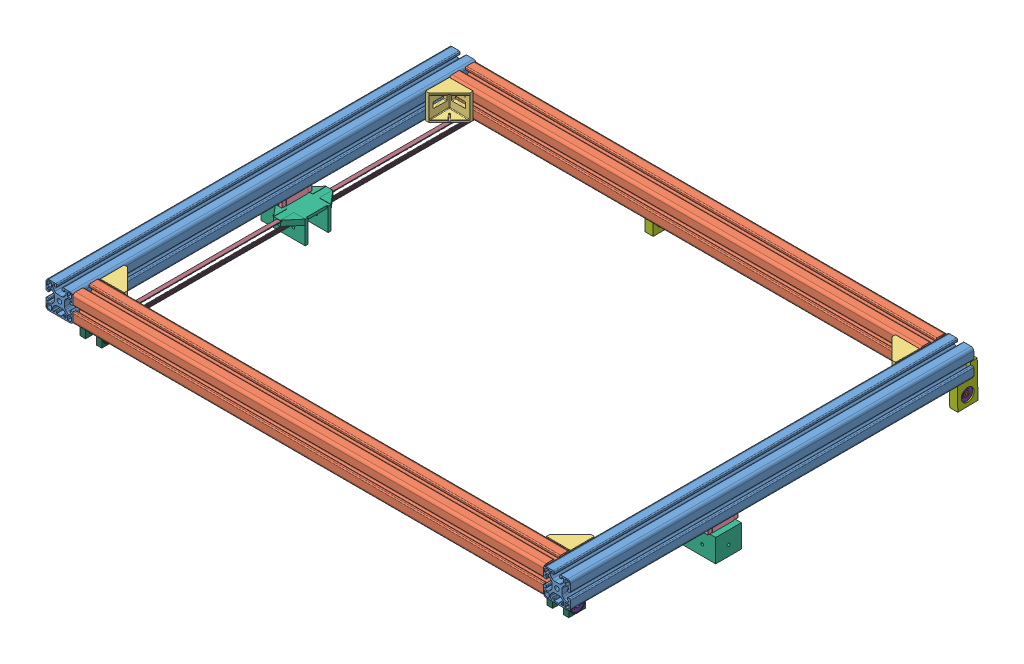
SolidWorks assembly y_axis, configuration Standard. Lengths in mm.
Overall size (783 87 614.14).
164 component instances, 17 part files, 52 mates.
Components (placement in the parent):
- 600mm_Motedis Profile 40x40 3N I-Type slot 8-1: 600mm_Motedis Profile 40x40 3N I-Type slot 8 [Standard] at (-18.8748 -20.0266 -250) size (40 40 600)
- 700mm_Motedis Profile 40x40 3N I-Type slot 8-1: 700mm_Motedis Profile 40x40 3N I-Type slot 8 [Standard] at (-282.8748 -20.0266 186) x (0 0 -1) z (1 0 0) size (40 40 700)
- bracket_40-1: bracket_40 [Standard] at (17.1252 -0.1016 190) x (-1 0 0) z (0 1 0) size (38.54 38.54 38)
- bracket_40-2: bracket_40 [Standard] at (17.1252 -0.1266 710) x (-1 0 0) z (0 -1 0) size (38.54 38.54 38)
- bracket_40-4: bracket_40 [Standard] at (717.1252 -0.1016 710) x (1 0 0) z (0 1 0) size (38.54 38.54 38)
- 700mm_Motedis Profile 40x40 3N I-Type slot 8-2: 700mm_Motedis Profile 40x40 3N I-Type slot 8 [Standard] at (1017.1252 -20.0266 714) x (0 0 1) z (-1 0 0) size (40 40 700)
- 600mm_Motedis Profile 40x40 3N I-Type slot 8-2: 600mm_Motedis Profile 40x40 3N I-Type slot 8 [Standard] at (753.1252 -20.0266 1150) x (-1 0 0) z (0 0 -1) size (40 40 600)
- bracket_40-5: bracket_40 [Standard] at (717.1252 0.0484 190) x (0 0 -1) z (0 1 0) size (38.54 38.54 38)
- MGN12H 1 R 500 ZF H M SS_FILE-1: MGN12H 1 R 500 ZF H M SS_FILE [Standard] at (802.4844 21.1866 187.5) x (1 0 0) z (0 -1 0) size (27 500 13) (flexible)
  - MGN12H 1 R 500 ZF H M SS_FILE-1: MGN12H 1 R 500 ZF H M SS_FILE [Standard] at (-65.3592 306.5221 39.2132) size (27 46.39 10)
  - MGN12H 1 R 500 ZF H M SS_FILE_1-1: MGN12H 1 R 500 ZF H M SS_FILE_1 [Standard] at (-65.3592 0 39.2132) size (12 500 8)
- MGN12H 1 R 500 ZF H M SS_FILE-2: MGN12H 1 R 500 ZF H M SS_FILE [Standard] at (62.4844 19.1866 187.5) x (1 0 0) z (0 -1 0) size (27 500 13) (flexible)
  - MGN12H 1 R 500 ZF H M SS_FILE-1: MGN12H 1 R 500 ZF H M SS_FILE [Standard] at (-65.3592 200.1469 39.2132) size (27 46.39 10)
  - MGN12H 1 R 500 ZF H M SS_FILE_1-1: MGN12H 1 R 500 ZF H M SS_FILE_1 [Standard] at (-65.3592 0 39.2132) size (12 500 8)
- mount_xaxis-1: mount_xaxis [Standard] at (9.6252 -37.0266 409.8469) size (66 34.4 78)
- mount_xaxis-2: mount_xaxis [Standard] at (724.6252 -35.0266 516.2221) x (-1 0 0) z (0 0 -1) size (66 34.4 78)
- drive_shaft_assembled-1: drive_shaft_assembled [Standard] at (97.0434 -122.3621 157.2312) x (0 -0.997563 0.069767) z (1 0 0) size (57.5 34.88 775) (flexible)
  - Lagerbock_assembled-1: Lagerbock_assembled [Standard] at (-81.1418 -2.5498 157.2355) x (0.069767 -0.997563 0) z (0 0 1) size (30 55 12)
    - Lagerbock-1: Lagerbock [Standard] at (0.8863 -1.2135 34) size (30 55 12)
    - 608-2Z-1: 608-2Z [Standard] at (0.8863 -1.2135 44) x (0 0 -1) z (1 0 0) size (7 22 22)
      - 608-2Z_PART1-1: 608-2Z_PART1 [Standard] at origin size (7 19.2 19.2)
      - 608-2Z_PART2-1: 608-2Z_PART2 [Standard] at origin size (7 22 22)
      - 608-2Z_PART3-1: 608-2Z_PART3 [Standard] at origin size (3.97 3.97 3.97)
      - 608-2Z_PART3-2: 608-2Z_PART3 [Standard] x (1 0 0) z (0 0.781831 0.62349) size (3.97 3.97 3.97)
      - 608-2Z_PART3-3: 608-2Z_PART3 [Standard] x (1 0 0) z (0 0.974928 -0.222521) size (3.97 3.97 3.97)
      - 608-2Z_PART3-4: 608-2Z_PART3 [Standard] x (1 0 0) z (0 0.433884 -0.900969) size (3.97 3.97 3.97)
      - 608-2Z_PART3-5: 608-2Z_PART3 [Standard] x (1 0 0) z (0 -0.433884 -0.900969) size (3.97 3.97 3.97)
      - 608-2Z_PART3-6: 608-2Z_PART3 [Standard] x (1 0 0) z (0 -0.974928 -0.222521) size (3.97 3.97 3.97)
      - 608-2Z_PART3-7: 608-2Z_PART3 [Standard] x (1 0 0) z (0 -0.781831 0.62349) size (3.97 3.97 3.97)
      - 608-2Z_PART4-1: 608-2Z_PART4 [Standard] at origin
      - 608-2Z_PART4-2: 608-2Z_PART4 [Standard] x (1 0 0) z (0 0.781831 0.62349)
      - 608-2Z_PART4-3: 608-2Z_PART4 [Standard] x (1 0 0) z (0 0.974928 -0.222521)
      - 608-2Z_PART4-4: 608-2Z_PART4 [Standard] x (1 0 0) z (0 0.433884 -0.900969)
      - 608-2Z_PART4-5: 608-2Z_PART4 [Standard] x (1 0 0) z (0 -0.433884 -0.900969)
      - 608-2Z_PART4-6: 608-2Z_PART4 [Standard] x (1 0 0) z (0 -0.974928 -0.222521)
      - 608-2Z_PART4-7: 608-2Z_PART4 [Standard] x (1 0 0) z (0 -0.781831 0.62349)
  - Lagerbock_assembled-2: Lagerbock_assembled [Standard] at (-81.1627 -2.5255 610.0818) x (0.091028 -0.995848 0) z (0 0 1) size (30 55 12)
    - Lagerbock-1: Lagerbock [Standard] at (0.8863 -1.2135 34) size (30 55 12)
    - 608-2Z-1: 608-2Z [Standard] at (0.8863 -1.2135 44) x (0 0 -1) z (1 0 0) size (7 22 22)
      - 608-2Z_PART1-1: 608-2Z_PART1 [Standard] at origin size (7 19.2 19.2)
      - 608-2Z_PART2-1: 608-2Z_PART2 [Standard] at origin size (7 22 22)
      - 608-2Z_PART3-1: 608-2Z_PART3 [Standard] at origin size (3.97 3.97 3.97)
      - 608-2Z_PART3-2: 608-2Z_PART3 [Standard] x (1 0 0) z (0 0.781831 0.62349) size (3.97 3.97 3.97)
      - 608-2Z_PART3-3: 608-2Z_PART3 [Standard] x (1 0 0) z (0 0.974928 -0.222521) size (3.97 3.97 3.97)
      - 608-2Z_PART3-4: 608-2Z_PART3 [Standard] x (1 0 0) z (0 0.433884 -0.900969) size (3.97 3.97 3.97)
      - 608-2Z_PART3-5: 608-2Z_PART3 [Standard] x (1 0 0) z (0 -0.433884 -0.900969) size (3.97 3.97 3.97)
      - 608-2Z_PART3-6: 608-2Z_PART3 [Standard] x (1 0 0) z (0 -0.974928 -0.222521) size (3.97 3.97 3.97)
      - 608-2Z_PART3-7: 608-2Z_PART3 [Standard] x (1 0 0) z (0 -0.781831 0.62349) size (3.97 3.97 3.97)
      - 608-2Z_PART4-1: 608-2Z_PART4 [Standard] at origin
      - 608-2Z_PART4-2: 608-2Z_PART4 [Standard] x (1 0 0) z (0 0.781831 0.62349)
      - 608-2Z_PART4-3: 608-2Z_PART4 [Standard] x (1 0 0) z (0 0.974928 -0.222521)
      - 608-2Z_PART4-4: 608-2Z_PART4 [Standard] x (1 0 0) z (0 0.433884 -0.900969)
      - 608-2Z_PART4-5: 608-2Z_PART4 [Standard] x (1 0 0) z (0 -0.433884 -0.900969)
      - 608-2Z_PART4-6: 608-2Z_PART4 [Standard] x (1 0 0) z (0 -0.974928 -0.222521)
      - 608-2Z_PART4-7: 608-2Z_PART4 [Standard] x (1 0 0) z (0 -0.781831 0.62349)
  - drive_shaft-1: drive_shaft [Standard] at (-82.2905 -3.5186 -112.9182) x (0 0 -1) z (0.760817 0.648966 0) size (770 8 8)
  - Pulley 1-1: Pulley 1 [Default] at (-82.2905 -3.5186 -83.5075) x (0 0 1) z (-0.994592 0.103863 0) size (14.8 16 16)
  - Pulley 1-2: Pulley 1 [Default] at (-82.2905 -3.5186 151.8444) x (0 0 1) z (-0.382013 0.924157 0) size (14.8 16 16)
  - Pulley 1-3: Pulley 1 [Default] at (-82.2905 -3.5186 610.1722) x (0 0 1) z (-0.74763 0.664116 0) size (14.8 16 16)
  - Lagerbock_assembled-3: Lagerbock_assembled [Standard] at (-81.1418 -2.5498 -152.9182) x (0.069767 -0.997563 0) z (0 0 1) size (30 55 12)
    - Lagerbock-1: Lagerbock [Standard] at (0.8863 -1.2135 34) size (30 55 12)
    - 608-2Z-1: 608-2Z [Standard] at (0.8863 -1.2135 44) x (0 0 -1) z (1 0 0) size (7 22 22)
      - 608-2Z_PART1-1: 608-2Z_PART1 [Standard] at origin size (7 19.2 19.2)
      - 608-2Z_PART2-1: 608-2Z_PART2 [Standard] at origin size (7 22 22)
      - 608-2Z_PART3-1: 608-2Z_PART3 [Standard] at origin size (3.97 3.97 3.97)
      - 608-2Z_PART3-2: 608-2Z_PART3 [Standard] x (1 0 0) z (0 0.781831 0.62349) size (3.97 3.97 3.97)
      - 608-2Z_PART3-3: 608-2Z_PART3 [Standard] x (1 0 0) z (0 0.974928 -0.222521) size (3.97 3.97 3.97)
      - 608-2Z_PART3-4: 608-2Z_PART3 [Standard] x (1 0 0) z (0 0.433884 -0.900969) size (3.97 3.97 3.97)
      - 608-2Z_PART3-5: 608-2Z_PART3 [Standard] x (1 0 0) z (0 -0.433884 -0.900969) size (3.97 3.97 3.97)
      - 608-2Z_PART3-6: 608-2Z_PART3 [Standard] x (1 0 0) z (0 -0.974928 -0.222521) size (3.97 3.97 3.97)
      - 608-2Z_PART3-7: 608-2Z_PART3 [Standard] x (1 0 0) z (0 -0.781831 0.62349) size (3.97 3.97 3.97)
      - 608-2Z_PART4-1: 608-2Z_PART4 [Standard] at origin
      - 608-2Z_PART4-2: 608-2Z_PART4 [Standard] x (1 0 0) z (0 0.781831 0.62349)
      - 608-2Z_PART4-3: 608-2Z_PART4 [Standard] x (1 0 0) z (0 0.974928 -0.222521)
      - 608-2Z_PART4-4: 608-2Z_PART4 [Standard] x (1 0 0) z (0 0.433884 -0.900969)
      - 608-2Z_PART4-5: 608-2Z_PART4 [Standard] x (1 0 0) z (0 -0.433884 -0.900969)
      - 608-2Z_PART4-6: 608-2Z_PART4 [Standard] x (1 0 0) z (0 -0.974928 -0.222521)
      - 608-2Z_PART4-7: 608-2Z_PART4 [Standard] x (1 0 0) z (0 -0.781831 0.62349)
- DYNAMIC-BLK-BELT-0.24W-4: DYNAMIC-BLK-BELT-0.24W [Default] at (717.2057 -46.3441 435) x (0 0 1) z (0 -1 0) size (573.27 6.02 13.27)
  - LINEAR-BLK-BELT-0.24W-1: LINEAR-BLK-BELT-0.24W [16.125"] at origin size (560 6.02 1.34)
  - RADUIS-BLK-BELT-0.24W-1: RADUIS-BLK-BELT-0.24W [Ø1.000] at (280 0 -6.3175) x (-1 0 0) z (0 0 -1) size (6.64 6.02 13.27)
  - RADUIS-BLK-BELT-0.24W-2: RADUIS-BLK-BELT-0.24W [Ø1.000] at (-280 0 -6.3175) size (6.64 6.02 13.27)
  - LINEAR-BLK-BELT-0.24W-2: LINEAR-BLK-BELT-0.24W [16.125"] at (0 0 -12.635) x (1 0 0) z (0 0 -1) size (560 6.02 1.34)
- DYNAMIC-BLK-BELT-0.24W-5: DYNAMIC-BLK-BELT-0.24W [Default] at (22.5458 -46.3441 435) x (0 0 1) z (0 -1 0) size (573.27 6.02 13.27)
  - LINEAR-BLK-BELT-0.24W-1: LINEAR-BLK-BELT-0.24W [16.125"] at origin size (560 6.02 1.34)
  - RADUIS-BLK-BELT-0.24W-1: RADUIS-BLK-BELT-0.24W [Ø1.000] at (280 0 -6.3175) x (-1 0 0) z (0 0 -1) size (6.64 6.02 13.27)
  - RADUIS-BLK-BELT-0.24W-2: RADUIS-BLK-BELT-0.24W [Ø1.000] at (-280 0 -6.3175) size (6.64 6.02 13.27)
  - LINEAR-BLK-BELT-0.24W-2: LINEAR-BLK-BELT-0.24W [16.125"] at (0 0 -12.635) x (1 0 0) z (0 0 -1) size (560 6.02 1.34)
- return_pully-1: return_pully [Standard] at (20.0584 -68.5266 714.9501) x (-1 0 0) z (0 1 0) size (38 45 34)
  - return_pully_holder-1: return_pully_holder [Standard] at (-1.4973 -12.4501 43) size (32 25 30)
  - 608-2Z-1: 608-2Z [Standard] at (-18.4973 0.0499 28.5) size (7 22 22)
    - 608-2Z_PART1-1: 608-2Z_PART1 [Standard] at origin size (7 19.2 19.2)
    - 608-2Z_PART2-1: 608-2Z_PART2 [Standard] at origin size (7 22 22)
    - 608-2Z_PART3-1: 608-2Z_PART3 [Standard] at origin size (3.97 3.97 3.97)
    - 608-2Z_PART3-2: 608-2Z_PART3 [Standard] x (1 0 0) z (0 0.781831 0.62349) size (3.97 3.97 3.97)
    - 608-2Z_PART3-3: 608-2Z_PART3 [Standard] x (1 0 0) z (0 0.974928 -0.222521) size (3.97 3.97 3.97)
    - 608-2Z_PART3-4: 608-2Z_PART3 [Standard] x (1 0 0) z (0 0.433884 -0.900969) size (3.97 3.97 3.97)
    - 608-2Z_PART3-5: 608-2Z_PART3 [Standard] x (1 0 0) z (0 -0.433884 -0.900969) size (3.97 3.97 3.97)
    - 608-2Z_PART3-6: 608-2Z_PART3 [Standard] x (1 0 0) z (0 -0.974928 -0.222521) size (3.97 3.97 3.97)
    - 608-2Z_PART3-7: 608-2Z_PART3 [Standard] x (1 0 0) z (0 -0.781831 0.62349) size (3.97 3.97 3.97)
    - 608-2Z_PART4-1: 608-2Z_PART4 [Standard] at origin
    - 608-2Z_PART4-2: 608-2Z_PART4 [Standard] x (1 0 0) z (0 0.781831 0.62349)
    - 608-2Z_PART4-3: 608-2Z_PART4 [Standard] x (1 0 0) z (0 0.974928 -0.222521)
    - 608-2Z_PART4-4: 608-2Z_PART4 [Standard] x (1 0 0) z (0 0.433884 -0.900969)
    - 608-2Z_PART4-5: 608-2Z_PART4 [Standard] x (1 0 0) z (0 -0.433884 -0.900969)
    - 608-2Z_PART4-6: 608-2Z_PART4 [Standard] x (1 0 0) z (0 -0.974928 -0.222521)
    - 608-2Z_PART4-7: 608-2Z_PART4 [Standard] x (1 0 0) z (0 -0.781831 0.62349)
  - 608-2Z-2: 608-2Z [Standard] at (8.5027 0.0499 28.5) size (7 22 22)
    - 608-2Z_PART1-1: 608-2Z_PART1 [Standard] at origin size (7 19.2 19.2)
    - 608-2Z_PART2-1: 608-2Z_PART2 [Standard] at origin size (7 22 22)
    - 608-2Z_PART3-1: 608-2Z_PART3 [Standard] at origin size (3.97 3.97 3.97)
    - 608-2Z_PART3-2: 608-2Z_PART3 [Standard] x (1 0 0) z (0 0.781831 0.62349) size (3.97 3.97 3.97)
    - 608-2Z_PART3-3: 608-2Z_PART3 [Standard] x (1 0 0) z (0 0.974928 -0.222521) size (3.97 3.97 3.97)
    - 608-2Z_PART3-4: 608-2Z_PART3 [Standard] x (1 0 0) z (0 0.433884 -0.900969) size (3.97 3.97 3.97)
    - 608-2Z_PART3-5: 608-2Z_PART3 [Standard] x (1 0 0) z (0 -0.433884 -0.900969) size (3.97 3.97 3.97)
    - 608-2Z_PART3-6: 608-2Z_PART3 [Standard] x (1 0 0) z (0 -0.974928 -0.222521) size (3.97 3.97 3.97)
    - 608-2Z_PART3-7: 608-2Z_PART3 [Standard] x (1 0 0) z (0 -0.781831 0.62349) size (3.97 3.97 3.97)
    - 608-2Z_PART4-1: 608-2Z_PART4 [Standard] at origin
    - 608-2Z_PART4-2: 608-2Z_PART4 [Standard] x (1 0 0) z (0 0.781831 0.62349)
    - 608-2Z_PART4-3: 608-2Z_PART4 [Standard] x (1 0 0) z (0 0.974928 -0.222521)
    - 608-2Z_PART4-4: 608-2Z_PART4 [Standard] x (1 0 0) z (0 0.433884 -0.900969)
    - 608-2Z_PART4-5: 608-2Z_PART4 [Standard] x (1 0 0) z (0 -0.433884 -0.900969)
    - 608-2Z_PART4-6: 608-2Z_PART4 [Standard] x (1 0 0) z (0 -0.974928 -0.222521)
    - 608-2Z_PART4-7: 608-2Z_PART4 [Standard] x (1 0 0) z (0 -0.781831 0.62349)
  - Pulley 1-1: Pulley 1 [Default] at (-11.4973 0.0499 28.5) size (14.8 16 16)
  - return_pully_tightener-1: return_pully_tightener [Standard] at (-1.4973 -17.4694 41.9425) x (1 0 0) z (0 1 0) size (38 15 45)
- return_pully-2: return_pully [Standard] at (714.7183 -68.5266 714.9501) x (-1 0 0) z (0 1 0) size (38 45 34)
  - return_pully_holder-1: return_pully_holder [Standard] at (-1.4973 -12.4501 43) size (32 25 30)
  - 608-2Z-1: 608-2Z [Standard] at (-18.4973 0.0499 28.5) size (7 22 22)
    - 608-2Z_PART1-1: 608-2Z_PART1 [Standard] at origin size (7 19.2 19.2)
    - 608-2Z_PART2-1: 608-2Z_PART2 [Standard] at origin size (7 22 22)
    - 608-2Z_PART3-1: 608-2Z_PART3 [Standard] at origin size (3.97 3.97 3.97)
    - 608-2Z_PART3-2: 608-2Z_PART3 [Standard] x (1 0 0) z (0 0.781831 0.62349) size (3.97 3.97 3.97)
    - 608-2Z_PART3-3: 608-2Z_PART3 [Standard] x (1 0 0) z (0 0.974928 -0.222521) size (3.97 3.97 3.97)
    - 608-2Z_PART3-4: 608-2Z_PART3 [Standard] x (1 0 0) z (0 0.433884 -0.900969) size (3.97 3.97 3.97)
    - 608-2Z_PART3-5: 608-2Z_PART3 [Standard] x (1 0 0) z (0 -0.433884 -0.900969) size (3.97 3.97 3.97)
    - 608-2Z_PART3-6: 608-2Z_PART3 [Standard] x (1 0 0) z (0 -0.974928 -0.222521) size (3.97 3.97 3.97)
    - 608-2Z_PART3-7: 608-2Z_PART3 [Standard] x (1 0 0) z (0 -0.781831 0.62349) size (3.97 3.97 3.97)
    - 608-2Z_PART4-1: 608-2Z_PART4 [Standard] at origin
    - 608-2Z_PART4-2: 608-2Z_PART4 [Standard] x (1 0 0) z (0 0.781831 0.62349)
    - 608-2Z_PART4-3: 608-2Z_PART4 [Standard] x (1 0 0) z (0 0.974928 -0.222521)
    - 608-2Z_PART4-4: 608-2Z_PART4 [Standard] x (1 0 0) z (0 0.433884 -0.900969)
    - 608-2Z_PART4-5: 608-2Z_PART4 [Standard] x (1 0 0) z (0 -0.433884 -0.900969)
    - 608-2Z_PART4-6: 608-2Z_PART4 [Standard] x (1 0 0) z (0 -0.974928 -0.222521)
    - 608-2Z_PART4-7: 608-2Z_PART4 [Standard] x (1 0 0) z (0 -0.781831 0.62349)
  - 608-2Z-2: 608-2Z [Standard] at (8.5027 0.0499 28.5) size (7 22 22)
    - 608-2Z_PART1-1: 608-2Z_PART1 [Standard] at origin size (7 19.2 19.2)
    - 608-2Z_PART2-1: 608-2Z_PART2 [Standard] at origin size (7 22 22)
    - 608-2Z_PART3-1: 608-2Z_PART3 [Standard] at origin size (3.97 3.97 3.97)
    - 608-2Z_PART3-2: 608-2Z_PART3 [Standard] x (1 0 0) z (0 0.781831 0.62349) size (3.97 3.97 3.97)
    - 608-2Z_PART3-3: 608-2Z_PART3 [Standard] x (1 0 0) z (0 0.974928 -0.222521) size (3.97 3.97 3.97)
    - 608-2Z_PART3-4: 608-2Z_PART3 [Standard] x (1 0 0) z (0 0.433884 -0.900969) size (3.97 3.97 3.97)
    - 608-2Z_PART3-5: 608-2Z_PART3 [Standard] x (1 0 0) z (0 -0.433884 -0.900969) size (3.97 3.97 3.97)
    - 608-2Z_PART3-6: 608-2Z_PART3 [Standard] x (1 0 0) z (0 -0.974928 -0.222521) size (3.97 3.97 3.97)
    - 608-2Z_PART3-7: 608-2Z_PART3 [Standard] x (1 0 0) z (0 -0.781831 0.62349) size (3.97 3.97 3.97)
    - 608-2Z_PART4-1: 608-2Z_PART4 [Standard] at origin
    - 608-2Z_PART4-2: 608-2Z_PART4 [Standard] x (1 0 0) z (0 0.781831 0.62349)
    - 608-2Z_PART4-3: 608-2Z_PART4 [Standard] x (1 0 0) z (0 0.974928 -0.222521)
    - 608-2Z_PART4-4: 608-2Z_PART4 [Standard] x (1 0 0) z (0 0.433884 -0.900969)
    - 608-2Z_PART4-5: 608-2Z_PART4 [Standard] x (1 0 0) z (0 -0.433884 -0.900969)
    - 608-2Z_PART4-6: 608-2Z_PART4 [Standard] x (1 0 0) z (0 -0.974928 -0.222521)
    - 608-2Z_PART4-7: 608-2Z_PART4 [Standard] x (1 0 0) z (0 -0.781831 0.62349)
  - Pulley 1-1: Pulley 1 [Default] at (-11.4973 0.0499 28.5) size (14.8 16 16)
  - return_pully_tightener-1: return_pully_tightener [Standard] at (-1.4973 -17.4694 41.9425) x (1 0 0) z (0 1 0) size (38 15 45)
Mates (geometry in assembly coordinates):
- Deckungsgleich1: coincident aligned: plane of 600mm_Motedis Profile 40x40 3N I-Type slot 8-1 through (-18.8748 -20.0266 150) normal (0 -1 0); plane of 700mm_Motedis Profile 40x40 3N I-Type slot 8-1 through (17.1252 -20.0266 186) normal (0 -1 0)
- Deckungsgleich2: coincident anti-aligned: plane of 600mm_Motedis Profile 40x40 3N I-Type slot 8-1 through (17.1252 -16.0266 150) normal (1 0 0); plane of 700mm_Motedis Profile 40x40 3N I-Type slot 8-1 through (17.1252 14.2658 175.1) normal (-1 0 0)
- Deckungsgleich3: coincident aligned: plane of 600mm_Motedis Profile 40x40 3N I-Type slot 8-1 through (-7.9748 14.2658 150) normal (0 0 -1); plane of 700mm_Motedis Profile 40x40 3N I-Type slot 8-1 through (17.1252 -16.0266 150) normal (0 0 -1)
- Deckungsgleich10: coincident anti-aligned: plane of 600mm_Motedis Profile 40x40 3N I-Type slot 8-1 through (17.1252 -16.0266 150) normal (1 0 0); plane of bracket_40-1 through (17.1252 18.8984 190) normal (-1 0 0)
- Deckungsgleich11: coincident anti-aligned: plane of 700mm_Motedis Profile 40x40 3N I-Type slot 8-1 through (17.1252 -5.6266 190) normal (0 0 1); plane of bracket_40-1 through (17.1252 18.8984 190) normal (0 0 -1)
- Deckungsgleich14: coincident: plane of 700mm_Motedis Profile 40x40 3N I-Type slot 8-1 through (17.1252 -4.1266 186.35) normal (0 1 0); line of bracket_40-1 through (52.6302 -4.1266 190.495) axis (-0.707107 0 0.707107)
- Deckungsgleich15: coincident anti-aligned: plane of 600mm_Motedis Profile 40x40 3N I-Type slot 8-1 through (17.1252 -16.0266 150) normal (1 0 0); plane of bracket_40-2 through (17.1252 -19.1266 710) normal (-1 0 0)
- Deckungsgleich16: coincident: plane of 600mm_Motedis Profile 40x40 3N I-Type slot 8-1 through (15.6252 -4.1266 150) normal (0 1 0); line of bracket_40-2 through (17.1252 -4.1266 703) axis (0.707107 0 0.707107)
- Deckungsgleich19: coincident aligned: plane of 700mm_Motedis Profile 40x40 3N I-Type slot 8-2 through (717.1252 -20.0266 714) normal (0 -1 0); plane of 600mm_Motedis Profile 40x40 3N I-Type slot 8-2 through (753.1252 -20.0266 750) normal (0 -1 0)
- Deckungsgleich20: coincident anti-aligned: plane of 700mm_Motedis Profile 40x40 3N I-Type slot 8-2 through (717.1252 14.2658 724.9) normal (1 0 0); plane of 600mm_Motedis Profile 40x40 3N I-Type slot 8-2 through (717.1252 -16.0266 750) normal (-1 0 0)
- Deckungsgleich21: coincident: line of bracket_40-4 through (681.6201 -4.1266 709.505) axis (0.707107 0 -0.707107); plane of 700mm_Motedis Profile 40x40 3N I-Type slot 8-2 through (717.1252 -4.1266 713.65) normal (0 1 0)
- Deckungsgleich22: coincident aligned: plane of 700mm_Motedis Profile 40x40 3N I-Type slot 8-2 through (717.1252 -16.0266 750) normal (0 0 1); plane of 600mm_Motedis Profile 40x40 3N I-Type slot 8-2 through (742.2252 14.2658 750) normal (0 0 1)
- Deckungsgleich23: coincident anti-aligned: plane of bracket_40-4 through (717.1252 18.8984 710) normal (0 0 1); plane of 700mm_Motedis Profile 40x40 3N I-Type slot 8-2 through (717.1252 -5.6266 710) normal (0 0 -1)
- Deckungsgleich24: coincident anti-aligned: plane of bracket_40-4 through (717.1252 18.8984 710) normal (1 0 0); plane of 600mm_Motedis Profile 40x40 3N I-Type slot 8-2 through (717.1252 -16.0266 750) normal (-1 0 0)
- Deckungsgleich25: coincident anti-aligned: plane of 600mm_Motedis Profile 40x40 3N I-Type slot 8-1 through (17.1252 -16.0266 150) normal (1 0 0); plane of 700mm_Motedis Profile 40x40 3N I-Type slot 8-2 through (17.1252 14.2658 724.9) normal (-1 0 0)
- Deckungsgleich27: coincident aligned: plane of 600mm_Motedis Profile 40x40 3N I-Type slot 8-1 through (-18.8748 -20.0266 150) normal (0 -1 0); plane of 700mm_Motedis Profile 40x40 3N I-Type slot 8-2 through (717.1252 -20.0266 714) normal (0 -1 0)
- Deckungsgleich28: coincident aligned: plane of 700mm_Motedis Profile 40x40 3N I-Type slot 8-1 through (17.1252 -16.0266 150) normal (0 0 -1); plane of 600mm_Motedis Profile 40x40 3N I-Type slot 8-2 through (742.2252 14.2658 150) normal (0 0 -1)
- Deckungsgleich29: coincident anti-aligned: plane of bracket_40-2 through (17.1252 -19.1266 710) normal (0 0 1); plane of 700mm_Motedis Profile 40x40 3N I-Type slot 8-2 through (717.1252 -5.6266 710) normal (0 0 -1)
- Deckungsgleich30: coincident anti-aligned: plane of 600mm_Motedis Profile 40x40 3N I-Type slot 8-2 through (717.1252 -16.0266 750) normal (-1 0 0); plane of bracket_40-5 through (717.1252 19.0484 190) normal (1 0 0)
- Deckungsgleich31: coincident anti-aligned: plane of bracket_40-5 through (717.1252 19.0484 190) normal (0 0 -1); plane of 700mm_Motedis Profile 40x40 3N I-Type slot 8-1 through (17.1252 -5.6266 190) normal (0 0 1)
- Deckungsgleich32: coincident: plane of 600mm_Motedis Profile 40x40 3N I-Type slot 8-2 through (720.7752 4.0734 750) normal (0 -1 0); line of bracket_40-5 through (715.3574 4.0734 224.2322) axis (0.707107 0 0.707107)
- Konzentrisch1: concentric anti-aligned: cylinder of 600mm_Motedis Profile 40x40 3N I-Type slot 8-2 through (737.1252 -20.0266 200) axis (0 -1 0) radius 1.25; cylinder of MGN12H 1 R 500 ZF H M SS_FILE-1/MGN12H 1 R 500 ZF H M SS_FILE_1-1 through (737.1252 -19.7766 200) axis (0 1 0) radius 1.75
- Deckungsgleich33: coincident: line of 600mm_Motedis Profile 40x40 3N I-Type slot 8-2 through (741.2252 -18.0266 750) axis (0 0 -1); plane of MGN12H 1 R 500 ZF H M SS_FILE-1/MGN12H 1 R 500 ZF H M SS_FILE_1-1 through (742.6252 -18.0266 687.5) normal (0 1 0)
- Konzentrisch3: concentric anti-aligned: cylinder of 600mm_Motedis Profile 40x40 3N I-Type slot 8-2 through (737.1252 -20.0266 675) axis (0 -1 0) radius 1.25; cylinder of MGN12H 1 R 500 ZF H M SS_FILE-1/MGN12H 1 R 500 ZF H M SS_FILE_1-1 through (737.1252 -19.7766 675) axis (0 1 0) radius 1.75
- Deckungsgleich34: coincident anti-aligned: plane of 600mm_Motedis Profile 40x40 3N I-Type slot 8-1 through (-18.8748 -20.0266 150) normal (0 -1 0); plane of MGN12H 1 R 500 ZF H M SS_FILE-2/MGN12H 1 R 500 ZF H M SS_FILE_1-1 through (2.6252 -20.0266 687.5) normal (0 1 0)
- Konzentrisch4: concentric anti-aligned: cylinder of 600mm_Motedis Profile 40x40 3N I-Type slot 8-1 through (-2.8748 -20.0266 200) axis (0 -1 0) radius 1.25; cylinder of MGN12H 1 R 500 ZF H M SS_FILE-2/MGN12H 1 R 500 ZF H M SS_FILE_1-1 through (-2.8748 -21.7766 200) axis (0 1 0) radius 1.75
- Konzentrisch6: concentric anti-aligned: cylinder of MGN12H 1 R 500 ZF H M SS_FILE-2/MGN12H 1 R 500 ZF H M SS_FILE_1-1 through (-2.8748 -21.7766 675) axis (0 1 0) radius 1.75; circle of 600mm_Motedis Profile 40x40 3N I-Type slot 8-1
- Konzentrisch7: concentric anti-aligned: cylinder of MGN12H 1 R 500 ZF H M SS_FILE-2/MGN12H 1 R 500 ZF H M SS_FILE-1 through (-12.8748 -31.2766 419.8469) axis (0 1 0) radius 1.25; cylinder of mount_xaxis-1 through (-12.8748 -33.0266 419.8469) axis (0 -1 0) radius 1.5
- Konzentrisch8: concentric anti-aligned: cylinder of MGN12H 1 R 500 ZF H M SS_FILE-2/MGN12H 1 R 500 ZF H M SS_FILE-1 through (7.1252 -31.2766 419.8469) axis (0 1 0) radius 1.25; cylinder of mount_xaxis-1 through (7.1252 -33.0266 419.8469) axis (0 -1 0) radius 1.5
- Konzentrisch9: concentric anti-aligned: cylinder of MGN12H 1 R 500 ZF H M SS_FILE-2/MGN12H 1 R 500 ZF H M SS_FILE-1 through (7.1252 -31.2766 399.8469) axis (0 1 0) radius 1.25; cylinder of mount_xaxis-1 through (7.1252 -33.0266 399.8469) axis (0 -1 0) radius 1.5
- Konzentrisch10: concentric anti-aligned: cylinder of MGN12H 1 R 500 ZF H M SS_FILE-2/MGN12H 1 R 500 ZF H M SS_FILE-1 through (-12.8748 -31.2766 399.8469) axis (0 1 0) radius 1.25; cylinder of mount_xaxis-1 through (-12.8748 -33.0266 399.8469) axis (0 -1 0) radius 1.5
- Deckungsgleich35: coincident anti-aligned: plane of MGN12H 1 R 500 ZF H M SS_FILE-2/MGN12H 1 R 500 ZF H M SS_FILE-1 through (-15.9748 -33.0266 426.0469) normal (0 -1 0); plane of mount_xaxis-1 through (9.6252 -33.0266 409.8469) normal (0 1 0)
- Konzentrisch11: concentric anti-aligned: cylinder of MGN12H 1 R 500 ZF H M SS_FILE-1/MGN12H 1 R 500 ZF H M SS_FILE-1 through (747.1252 -29.2766 506.2221) axis (0 1 0) radius 1.25; cylinder of mount_xaxis-2 through (747.1252 -31.0266 506.2221) axis (0 -1 0) radius 1.5
- Konzentrisch12: concentric anti-aligned: cylinder of MGN12H 1 R 500 ZF H M SS_FILE-1/MGN12H 1 R 500 ZF H M SS_FILE-1 through (747.1252 -29.2766 526.2221) axis (0 1 0) radius 1.25; cylinder of mount_xaxis-2 through (747.1252 -31.0266 526.2221) axis (0 -1 0) radius 1.5
- Deckungsgleich36: coincident anti-aligned: plane of MGN12H 1 R 500 ZF H M SS_FILE-1/MGN12H 1 R 500 ZF H M SS_FILE-1 through (724.0252 -31.0266 532.4221) normal (0 -1 0); plane of mount_xaxis-2 through (724.6252 -31.0266 516.2221) normal (0 1 0)
- Konzentrisch13: concentric anti-aligned: cylinder of MGN12H 1 R 500 ZF H M SS_FILE-1/MGN12H 1 R 500 ZF H M SS_FILE-1 through (727.1252 -29.2766 526.2221) axis (0 1 0) radius 1.25; cylinder of mount_xaxis-2 through (727.1252 -31.0266 526.2221) axis (0 -1 0) radius 1.5
- Konzentrisch14: concentric anti-aligned: cylinder of MGN12H 1 R 500 ZF H M SS_FILE-1/MGN12H 1 R 500 ZF H M SS_FILE-1 through (727.1252 -29.2766 506.2221) axis (0 1 0) radius 1.25; cylinder of mount_xaxis-2 through (727.1252 -31.0266 506.2221) axis (0 -1 0) radius 1.5
- Deckungsgleich43: coincident anti-aligned: plane of 700mm_Motedis Profile 40x40 3N I-Type slot 8-1 through (17.1252 -20.0266 186) normal (0 -1 0); plane of drive_shaft_assembled-1/Lagerbock_assembled-1/Lagerbock-1 through (300.2789 -20.0266 170) normal (0 1 0)
- Deckungsgleich46: coincident: line of 600mm_Motedis Profile 40x40 3N I-Type slot 8-2 through (753.1252 -20.0266 750) axis (0 0 -1); plane of drive_shaft_assembled-1/Lagerbock_assembled-2/Lagerbock-1 through (753.1252 -40.0266 155) normal (1 0 0)
- Deckungsgleich47: coincident anti-aligned: plane of 600mm_Motedis Profile 40x40 3N I-Type slot 8-1 through (-7.9748 14.2658 150) normal (0 0 -1); plane of drive_shaft_assembled-1/Lagerbock_assembled-3/Lagerbock-1 through (-9.8748 -0.0266 150) normal (0 0 1)
- Konzentrisch15: concentric anti-aligned: cylinder of drive_shaft_assembled-1/Pulley 1-3 through (707.2156 -40.0266 155) axis (-1 0 0) radius 8; cylinder of DYNAMIC-BLK-BELT-0.24W-4/RADUIS-BLK-BELT-0.24W-2 through (714.1958 -40.0266 155) axis (1 0 0) radius 6.635
- Parallel1: parallel aligned: plane of mount_xaxis-2 through (709.6252 -38.6266 477.3221) normal (0 -1 0); plane of DYNAMIC-BLK-BELT-0.24W-4/LINEAR-BLK-BELT-0.24W-1 through (714.1958 -46.6616 155) normal (0 -1 0)
- Konzentrisch16: concentric anti-aligned: cylinder of drive_shaft_assembled-1/Pulley 1-1 through (13.5359 -40.0266 155) axis (-1 0 0) radius 8; cylinder of DYNAMIC-BLK-BELT-0.24W-5/RADUIS-BLK-BELT-0.24W-2 through (19.5359 -40.0266 155) axis (1 0 0) radius 6.635
- Parallel2: parallel aligned: plane of mount_xaxis-1 through (24.6252 -40.6266 370.7469) normal (0 -1 0); plane of DYNAMIC-BLK-BELT-0.24W-5/LINEAR-BLK-BELT-0.24W-1 through (19.5359 -46.6616 155) normal (0 -1 0)
- Deckungsgleich50: coincident anti-aligned: plane of drive_shaft_assembled-1/Pulley 1-1 through (19.5359 -41.2376 148.1055) normal (1 0 0); plane of DYNAMIC-BLK-BELT-0.24W-5/RADUIS-BLK-BELT-0.24W-2 through (19.5359 -40.0266 155) normal (-1 0 0)
- Deckungsgleich51: coincident anti-aligned: plane of drive_shaft_assembled-1/Pulley 1-3 through (720.2156 -44.6004 150.5234) normal (-1 0 0); plane of DYNAMIC-BLK-BELT-0.24W-4/RADUIS-BLK-BELT-0.24W-2 through (720.2156 -40.0266 155) normal (1 0 0)
- Konzentrisch18: concentric aligned: cylinder of DYNAMIC-BLK-BELT-0.24W-5/RADUIS-BLK-BELT-0.24W-1 through (19.5359 -40.0266 715) axis (1 0 0) radius 6.635; cylinder of return_pully-1/608-2Z-1/608-2Z_PART1-1 through (-11.4443 -40.0266 715) axis (1 0 0) radius 4
- Parallel3: parallel anti-aligned: plane of 700mm_Motedis Profile 40x40 3N I-Type slot 8-2 through (717.1252 -20.0266 714) normal (0 -1 0); plane of return_pully-1/return_pully_tightener-1 through (2.5557 -17.5266 737.4807) normal (0 1 0)
- Deckungsgleich53: coincident anti-aligned: plane of DYNAMIC-BLK-BELT-0.24W-5/RADUIS-BLK-BELT-0.24W-1 through (25.5557 -40.0266 715) normal (1 0 0); plane of return_pully-1/Pulley 1-1 through (25.5557 -40.0266 722) normal (-1 0 0)
- Konzentrisch20: concentric aligned: cylinder of DYNAMIC-BLK-BELT-0.24W-4/RADUIS-BLK-BELT-0.24W-1 through (714.1958 -40.0266 715) axis (1 0 0) radius 6.635; cylinder of return_pully-2/608-2Z-1/608-2Z_PART1-1 through (683.2156 -40.0266 715) axis (1 0 0) radius 4
- Parallel4: parallel anti-aligned: plane of 600mm_Motedis Profile 40x40 3N I-Type slot 8-2 through (753.1252 -20.0266 750) normal (0 -1 0); plane of return_pully-2/return_pully_tightener-1 through (697.2156 -17.5266 737.4807) normal (0 1 0)
- Deckungsgleich55: coincident anti-aligned: plane of DYNAMIC-BLK-BELT-0.24W-4/LINEAR-BLK-BELT-0.24W-1 through (720.2156 -46.3441 435) normal (1 0 0); plane of return_pully-2/Pulley 1-1 through (720.2156 -40.0266 722) normal (-1 0 0)
